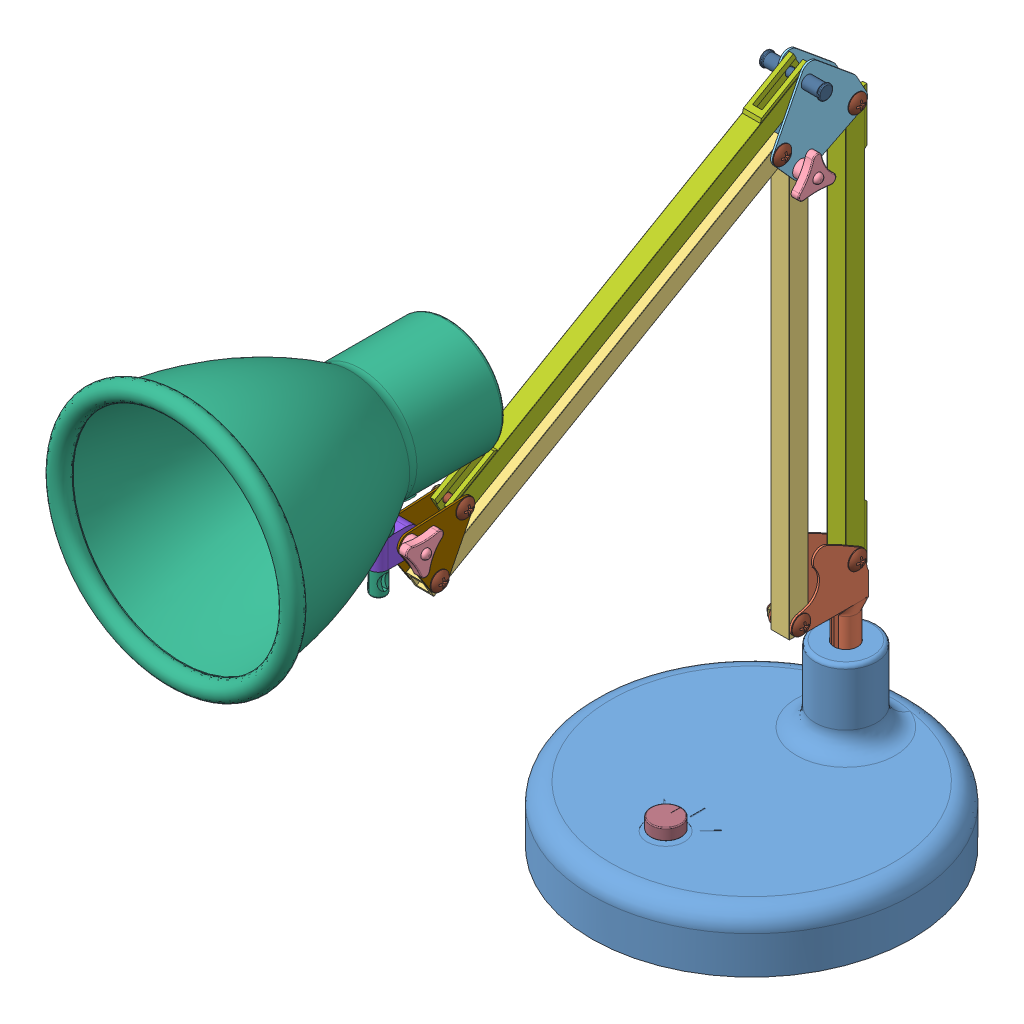
SolidWorks assembly Assem1, configuration Default. Lengths in mm.
Overall size (170 360.77 395.76).
30 component instances, 13 part files, 66 mates.
Components (placement in the parent):
- base-1: base [Default] at (-10.4854 -28.4138 1.0584) size (170 70 170)
- buttom holder-1: buttom holder [Default] at (-15.4854 66.5862 -48.9416) x (-1 0 0) z (0 0 -1) size (12.1 90 41.05)
- vertical axes-1: vertical axes [Default] at (-10.4854 61.5862 -18.9416) size (10 220 10)
- level joint mounted-1: level joint mounted [Default] at (0.5146 205.665 193.0971) x (1 0 0) z (0 0.85639 0.516329) size (11 17.99 20)
- middle joint-1: middle joint [Default] at (-15.9854 291.5862 -48.9416) x (-1 0 0) z (0 0 -1) size (1 51.48 50.61)
- Shade-1: Shade [Default] at (-10.4854 265.393 234.3146) x (-1 0 0) z (0 0 -1) size (133.92 144.96 150)
- second vertical axes-1: second vertical axes [Default] at (-10.4854 317.0247 -26.8364) x (1 0 0) z (0 -0.866025 -0.5) size (10 220 11.5)
- second vertical axes-2: second vertical axes [Default] at (-10.4854 296.5862 -48.9416) x (-1 0 0) z (0 0 1) size (10 220 11.5)
- middle joint-2: middle joint [Default] at (-4.9854 291.5862 -48.9416) x (-1 0 0) z (0 0 -1) size (1 51.48 50.61)
- vertical axes-2: vertical axes [Default] at (-10.4854 290.2666 -13.2717) x (-1 0 0) z (0 0.866025 0.5) size (10 220 10)
- shade mounted-1: shade mounted [Default] at (-10.4854 207.893 196.8146) x (-1 0 0) z (0 0 -1) size (10 15 22.5)
- top joint-4: top joint [Default] at (-5.4854 194.9475 166.7488) x (1 0 0) z (0 -0.891939 0.452157) size (1 36.05 40.1)
- top joint-5: top joint [Default] at (-16.4854 194.9475 166.7488) x (1 0 0) z (0 -0.891939 0.452157) size (1 36.05 40.1)
- level joint mounted-2: level joint mounted [Default] at (0.5146 272.1966 -18.8966) size (11 17.99 20)
- middle joint spring-2: middle joint spring [Default] at (-10.4854 314.5247 -22.5063) x (-1 0 0) z (0 0.98499 -0.172611) size (32 7.5 7.5)
- truss head screw_ai-25: truss head screw_ai [CR-THMS 0.164-36x0.625x0.625-N] at (-1.8946 182.7666 172.9237) x (-1 0 0) z (0 0 -1) size (18.42 9.75 9.75)
- truss head screw_ai-26: truss head screw_ai [CR-THMS 0.164-36x0.625x0.625-N] at (-1.8946 209.5247 159.359) x (-1 0 0) z (0 0 -1) size (18.42 9.75 9.75)
- truss head screw_ai-27: truss head screw_ai [CR-THMS 0.164-36x0.625x0.625-N] at (-1.8946 291.5862 -48.9416) x (-1 0 0) z (0 0 -1) size (18.42 9.75 9.75)
- truss head screw_ai-28: truss head screw_ai [CR-THMS 0.164-36x0.625x0.625-N] at (-1.8946 287.7666 -8.9416) x (-1 0 0) z (0 0 -1) size (18.42 9.75 9.75)
- truss head screw_ai-29: truss head screw_ai [CR-THMS 0.164-36x0.625x0.625-N] at (-1.8946 81.5862 -48.9416) x (-1 0 0) z (0 0 -1) size (18.42 9.75 9.75)
- truss head screw_ai-30: truss head screw_ai [CR-THMS 0.164-36x0.625x0.625-N] at (-1.8946 66.5862 -18.9416) x (-1 0 0) z (0 0 -1) size (18.42 9.75 9.75)
- truss head screw_ai-31: truss head screw_ai [CR-THMS 0.164-36x0.625x0.625-N] at (-19.0762 276.5862 -18.9416) size (18.42 9.75 9.75)
- truss head screw_ai-32: truss head screw_ai [CR-THMS 0.164-36x0.625x0.625-N] at (-19.0762 207.9523 189.4316) size (18.42 9.75 9.75)
- machine screw nut hex_ai-8: machine screw nut hex_ai [MSHXNUT 0.112-40-S-N] at (-18.9746 291.5862 -48.9416) x (0 0 1) z (-1 0 0) size (6.35 7.33 2.49)
- machine screw nut hex_ai-9: machine screw nut hex_ai [MSHXNUT 0.112-40-S-N] at (-18.9746 287.7666 -8.9416) x (0 0 1) z (-1 0 0) size (6.35 7.33 2.49)
- machine screw nut hex_ai-10: machine screw nut hex_ai [MSHXNUT 0.112-40-S-N] at (-18.9746 209.5247 159.359) x (0 0 1) z (-1 0 0) size (6.35 7.33 2.49)
- machine screw nut hex_ai-11: machine screw nut hex_ai [MSHXNUT 0.112-40-S-N] at (-18.9746 182.7666 172.9237) x (0 0 1) z (-1 0 0) size (6.35 7.33 2.49)
- machine screw nut hex_ai-13: machine screw nut hex_ai [MSHXNUT 0.112-40-S-N] at (-18.9746 66.5862 -18.9416) x (0 0 1) z (-1 0 0) size (6.35 7.33 2.49)
- machine screw nut hex_ai-14: machine screw nut hex_ai [MSHXNUT 0.112-40-S-N] at (-18.9746 81.5862 -48.9416) x (0 0 1) z (-1 0 0) size (6.35 7.33 2.49)
- Knob-1: Knob [Default] at (-10.4854 -3.4138 46.6129) size (16 12 16)
Mates (geometry in assembly coordinates):
- Concentric1: concentric anti-aligned: cylinder of base-1 through (-10.4854 41.5862 -48.9416) axis (0 -1 0) radius 6.25; cylinder of buttom holder-1 through (-10.4854 6.5862 -48.9416) axis (0 1 0) radius 6
- Coincident9: coincident anti-aligned: plane of buttom holder-1 through (-5.4854 82.0218 -18.9416) normal (-1 0 0); plane of second vertical axes-2 through (-5.4854 76.5862 -43.9416) normal (1 0 0)
- Coincident10: coincident aligned: line of buttom holder-1 through (-4.4854 81.5862 -48.9416) axis (-1 0 0); line of second vertical axes-2 through (-5.4854 81.5862 -48.9416) axis (-1 0 0)
- Distance1: distance = 30 mm anti-aligned: plane of buttom holder-1 through (-10.4854 6.5862 -48.9416) normal (0 -1 0); plane of base-1 through (-10.4854 -23.4138 1.0584) normal (0 1 0)
- Coincident26: coincident anti-aligned: line of buttom holder-1 through (-4.4854 66.5862 -18.9416) axis (-1 0 0); line of vertical axes-1 through (-6.9854 66.5862 -18.9416) axis (1 0 0)
- Coincident27: coincident anti-aligned: plane of buttom holder-1 through (-5.4854 82.0218 -18.9416) normal (-1 0 0); plane of vertical axes-1 through (-5.4854 281.5862 -13.9416) normal (1 0 0)
- Coincident29: coincident anti-aligned: line of middle joint-1 through (-16.4854 291.5862 -48.9416) axis (1 0 0); line of second vertical axes-2 through (-13.9854 291.5862 -48.9416) axis (-1 0 0)
- Coincident30: coincident aligned: line of vertical axes-1 through (-15.4854 276.5862 -18.9416) axis (1 0 0); line of middle joint-1 through (-16.4854 276.5862 -18.9416) axis (1 0 0)
- Coincident31: coincident anti-aligned: plane of middle joint-1 through (-15.4854 301.5862 -44.2507) normal (1 0 0); plane of second vertical axes-2 through (-15.4854 76.5862 -43.9416) normal (-1 0 0)
- Coincident32: coincident anti-aligned: line of second vertical axes-2 through (-5.4854 291.5862 -48.9416) axis (-1 0 0); line of middle joint-2 through (-5.4854 291.5862 -48.9416) axis (1 0 0)
- Coincident33: coincident aligned: line of vertical axes-1 through (-6.9854 276.5862 -18.9416) axis (1 0 0); line of middle joint-2 through (-5.4854 276.5862 -18.9416) axis (1 0 0)
- Coincident34: coincident anti-aligned: plane of vertical axes-1 through (-5.4854 281.5862 -13.9416) normal (1 0 0); plane of middle joint-2 through (-5.4854 301.5862 -44.2507) normal (-1 0 0)
- Coincident35: coincident aligned: line of second vertical axes-1 through (-6.9854 314.5247 -22.5063) axis (1 0 0); line of middle joint-2 through (-5.4854 314.5247 -22.5063) axis (1 0 0)
- Coincident36: coincident anti-aligned: plane of second vertical axes-1 through (-5.4854 202.6946 161.1892) normal (1 0 0); plane of middle joint-2 through (-5.4854 301.5862 -44.2507) normal (-1 0 0)
- Coincident37: coincident anti-aligned: line of middle joint-2 through (-5.4854 287.7666 -8.9416) axis (1 0 0); line of vertical axes-2 through (-5.4854 287.7666 -8.9416) axis (-1 0 0)
- Coincident38: coincident anti-aligned: plane of middle joint-2 through (-5.4854 301.5862 -44.2507) normal (-1 0 0); plane of vertical axes-2 through (-5.4854 184.5967 179.7539) normal (1 0 0)
- Coincident59: coincident anti-aligned: line of second vertical axes-1 through (-15.4854 209.5247 159.359) axis (1 0 0); line of top joint-4 through (-4.4854 209.5247 159.359) axis (-1 0 0)
- Coincident60: coincident anti-aligned: line of shade mounted-1 through (-15.4854 207.893 189.3146) axis (1 0 0); line of top joint-4 through (-4.4854 207.893 189.3146) axis (-1 0 0)
- Coincident61: coincident aligned: line of vertical axes-2 through (-5.4854 182.7666 172.9237) axis (-1 0 0); line of top joint-4 through (-4.4854 182.7666 172.9237) axis (-1 0 0)
- Coincident62: coincident anti-aligned: line of second vertical axes-1 through (-15.4854 209.5247 159.359) axis (1 0 0); line of top joint-5 through (-15.4854 209.5247 159.359) axis (-1 0 0)
- Coincident65: coincident aligned: line of vertical axes-2 through (-13.9854 182.7666 172.9237) axis (-1 0 0); line of top joint-5 through (-15.4854 182.7666 172.9237) axis (-1 0 0)
- Coincident66: coincident anti-aligned: line of shade mounted-1 through (-15.4854 207.893 189.3146) axis (1 0 0); line of top joint-5 through (-15.4854 207.893 189.3146) axis (-1 0 0)
- Coincident69: coincident aligned: line of Shade-1 through (-10.4854 188.393 199.3146) axis (0 1 0); line of shade mounted-1 through (-10.4854 200.393 199.3146) axis (0 1 0)
- Coincident70: coincident anti-aligned: plane of shade mounted-1 through (-15.4854 207.893 196.8146) normal (-1 0 0); plane of top joint-5 through (-15.4854 209.5964 159.2492) normal (1 0 0)
- Coincident71: coincident anti-aligned: plane of shade mounted-1 through (-5.4854 207.893 196.8146) normal (1 0 0); plane of top joint-4 through (-5.4854 209.5964 159.2492) normal (-1 0 0)
- Coincident72: coincident anti-aligned: plane of Shade-1 through (-10.4854 215.393 199.3146) normal (0 -1 0); plane of shade mounted-1 through (-15.4854 215.393 196.8146) normal (0 1 0)
- Coincident73: coincident anti-aligned: plane of second vertical axes-1 through (-15.4854 202.6946 161.1892) normal (-1 0 0); plane of top joint-5 through (-15.4854 209.5964 159.2492) normal (1 0 0)
- Coincident74: coincident anti-aligned: plane of vertical axes-2 through (-5.4854 184.5967 179.7539) normal (1 0 0); plane of top joint-4 through (-5.4854 209.5964 159.2492) normal (-1 0 0)
- Coincident75: coincident aligned: line of middle joint-1 through (-16.4854 314.5247 -22.5063) axis (1 0 0); line of middle joint spring-2 through (-16.4854 314.5247 -22.5063) axis (1 0 0)
- Coincident76: coincident anti-aligned: plane of middle joint-1 through (-16.4854 301.5862 -44.2507) normal (-1 0 0); plane of middle joint spring-2 through (-16.4854 314.5247 -22.5063) normal (1 0 0)
- Coincident77: coincident aligned: line of middle joint-2 through (-5.4854 276.5862 -18.9416) axis (1 0 0); line of level joint mounted-2 through (-4.4854 276.5862 -18.9416) axis (1 0 0)
- Coincident78: coincident anti-aligned: plane of middle joint-2 through (-4.4854 301.5862 -44.2507) normal (1 0 0); plane of level joint mounted-2 through (-4.4854 276.5862 -18.9416) normal (-1 0 0)
- Coincident79: coincident aligned: line of level joint mounted-1 through (-4.4854 207.893 189.3146) axis (1 0 0); line of shade mounted-1 through (-15.4854 207.893 189.3146) axis (1 0 0)
- Coincident80: coincident anti-aligned: plane of level joint mounted-1 through (-4.4854 207.893 189.3146) normal (-1 0 0); plane of top joint-4 through (-4.4854 209.5964 159.2492) normal (1 0 0)
- Concentric27: concentric anti-aligned: cylinder of top joint-4 through (-4.4854 182.7666 172.9237) axis (-1 0 0) radius 2.25; cylinder of truss head screw_ai-25 through (23.5054 182.7666 172.9237) axis (1 0 0) radius 4.8768
- Coincident105: coincident anti-aligned: plane of top joint-4 through (-4.4854 209.5964 159.2492) normal (1 0 0); plane of truss head screw_ai-25 through (-4.4854 184.8494 172.9237) normal (-1 0 0)
- Concentric28: concentric anti-aligned: cylinder of top joint-4 through (-4.4854 209.5247 159.359) axis (-1 0 0) radius 2.25; cylinder of truss head screw_ai-26 through (23.5054 209.5247 159.359) axis (1 0 0) radius 4.8768
- Coincident106: coincident anti-aligned: plane of top joint-4 through (-4.4854 209.5964 159.2492) normal (1 0 0); plane of truss head screw_ai-26 through (-4.4854 211.6075 159.359) normal (-1 0 0)
- Concentric29: concentric aligned: cylinder of middle joint-2 through (-5.4854 291.5862 -48.9416) axis (1 0 0) radius 2.25; cylinder of truss head screw_ai-27 through (23.5054 291.5862 -48.9416) axis (1 0 0) radius 4.8768
- Coincident107: coincident anti-aligned: plane of middle joint-2 through (-4.4854 301.5862 -44.2507) normal (1 0 0); plane of truss head screw_ai-27 through (-4.4854 293.669 -48.9416) normal (-1 0 0)
- Concentric30: concentric aligned: cylinder of middle joint-2 through (-5.4854 287.7666 -8.9416) axis (1 0 0) radius 2.25; cylinder of truss head screw_ai-28 through (23.5054 287.7666 -8.9416) axis (1 0 0) radius 4.8768
- Coincident108: coincident anti-aligned: plane of middle joint-2 through (-4.4854 301.5862 -44.2507) normal (1 0 0); plane of truss head screw_ai-28 through (-4.4854 289.8494 -8.9416) normal (-1 0 0)
- Concentric31: concentric anti-aligned: cylinder of buttom holder-1 through (-4.4854 81.5862 -48.9416) axis (-1 0 0) radius 2.25; cylinder of truss head screw_ai-29 through (23.5054 81.5862 -48.9416) axis (1 0 0) radius 4.8768
- Coincident109: coincident anti-aligned: plane of buttom holder-1 through (-4.4854 73.5862 -54.9416) normal (1 0 0); plane of truss head screw_ai-29 through (-4.4854 83.669 -48.9416) normal (-1 0 0)
- Concentric32: concentric anti-aligned: cylinder of buttom holder-1 through (-4.4854 66.5862 -18.9416) axis (-1 0 0) radius 2.25; cylinder of truss head screw_ai-30 through (23.5054 66.5862 -18.9416) axis (1 0 0) radius 4.8768
- Coincident110: coincident anti-aligned: plane of buttom holder-1 through (-4.4854 73.5862 -54.9416) normal (1 0 0); plane of truss head screw_ai-30 through (-4.4854 68.669 -18.9416) normal (-1 0 0)
- Concentric331: concentric anti-aligned: cylinder of middle joint-1 through (-16.4854 276.5862 -18.9416) axis (1 0 0) radius 2.25; cylinder of truss head screw_ai-31 through (-44.4762 276.5862 -18.9416) axis (-1 0 0) radius 4.8768
- Coincident1111: coincident anti-aligned: plane of middle joint-1 through (-16.4854 301.5862 -44.2507) normal (-1 0 0); plane of truss head screw_ai-31 through (-16.4854 278.669 -18.9416) normal (1 0 0)
- Concentric34: concentric aligned: cylinder of top joint-5 through (-15.4854 207.9523 189.4316) axis (-1 0 0) radius 4.9344; cylinder of truss head screw_ai-32 through (-44.4762 207.9523 189.4316) axis (-1 0 0) radius 4.8768
- Coincident112: coincident anti-aligned: plane of top joint-5 through (-16.4854 209.5964 159.2492) normal (-1 0 0); plane of truss head screw_ai-32 through (-16.4854 210.0351 189.4316) normal (1 0 0)
- Concentric35: concentric anti-aligned: cylinder of middle joint-1 through (-16.4854 291.5862 -48.9416) axis (1 0 0) radius 2.25; cylinder of machine screw nut hex_ai-8 through (6.0629 291.5862 -48.9416) axis (-1 0 0) radius 1.4224
- Coincident113: coincident anti-aligned: plane of middle joint-1 through (-16.4854 301.5862 -44.2507) normal (-1 0 0); plane of machine screw nut hex_ai-8 through (-16.4854 295.2524 -48.9416) normal (1 0 0)
- Concentric36: concentric anti-aligned: cylinder of middle joint-1 through (-16.4854 287.7666 -8.9416) axis (1 0 0) radius 2.25; cylinder of machine screw nut hex_ai-9 through (6.0629 287.7666 -8.9416) axis (-1 0 0) radius 1.4224
- Coincident114: coincident anti-aligned: plane of middle joint-1 through (-16.4854 301.5862 -44.2507) normal (-1 0 0); plane of machine screw nut hex_ai-9 through (-16.4854 291.4327 -8.9416) normal (1 0 0)
- Concentric37: concentric aligned: cylinder of top joint-5 through (-15.4854 209.5247 159.359) axis (-1 0 0) radius 2.25; cylinder of machine screw nut hex_ai-10 through (6.0629 209.5247 159.359) axis (-1 0 0) radius 1.4224
- Coincident115: coincident anti-aligned: plane of top joint-5 through (-16.4854 209.5964 159.2492) normal (-1 0 0); plane of machine screw nut hex_ai-10 through (-16.4854 213.1909 159.359) normal (1 0 0)
- Concentric38: concentric aligned: cylinder of top joint-5 through (-15.4854 182.7666 172.9237) axis (-1 0 0) radius 2.25; cylinder of machine screw nut hex_ai-11 through (6.0629 182.7666 172.9237) axis (-1 0 0) radius 1.4224
- Coincident116: coincident anti-aligned: plane of top joint-5 through (-16.4854 209.5964 159.2492) normal (-1 0 0); plane of machine screw nut hex_ai-11 through (-16.4854 186.4327 172.9237) normal (1 0 0)
- Concentric39: concentric anti-aligned: cylinder of buttom holder-1 through (-16.4854 66.5862 -18.9416) axis (1 0 0) radius 2.25; cylinder of machine screw nut hex_ai-13 through (6.0629 66.5862 -18.9416) axis (-1 0 0) radius 1.4224
- Coincident117: coincident anti-aligned: plane of buttom holder-1 through (-16.4854 82.0218 -18.9416) normal (-1 0 0); plane of machine screw nut hex_ai-13 through (-16.4854 70.2524 -18.9416) normal (1 0 0)
- Concentric40: concentric anti-aligned: cylinder of buttom holder-1 through (-16.4854 81.5862 -48.9416) axis (1 0 0) radius 2.25; cylinder of machine screw nut hex_ai-14 through (6.0629 81.5862 -48.9416) axis (-1 0 0) radius 1.4224
- Coincident118: coincident anti-aligned: plane of buttom holder-1 through (-16.4854 82.0218 -18.9416) normal (-1 0 0); plane of machine screw nut hex_ai-14 through (-16.4854 85.2524 -48.9416) normal (1 0 0)
- Perpendicular2: perpendicular: plane of base-1 through (-10.4854 1.5862 1.0584) normal (0 1 0); plane of vertical axes-1 through (-15.4854 281.5862 -13.9416) normal (-1 0 0)
- Angle4: planar angle = 1.047198 rad anti-aligned: plane of vertical axes-2 through (-15.4854 175.9364 174.7539) normal (0 -0.866025 -0.5); plane of vertical axes-1 through (-5.4854 281.5862 -13.9416) normal (0 0 1)
- Coincident1112: coincident anti-aligned: line of base-1 through (-10.4854 -3.4138 46.6129) axis (0 1 0); line of Knob-1 through (-10.4854 2.5862 46.6129) axis (0 -1 0)
- Coincident1113: coincident anti-aligned: plane of base-1 through (-10.4854 -3.4138 46.6129) normal (0 1 0); plane of Knob-1 through (-10.4854 -3.4138 46.6129) normal (0 -1 0)
